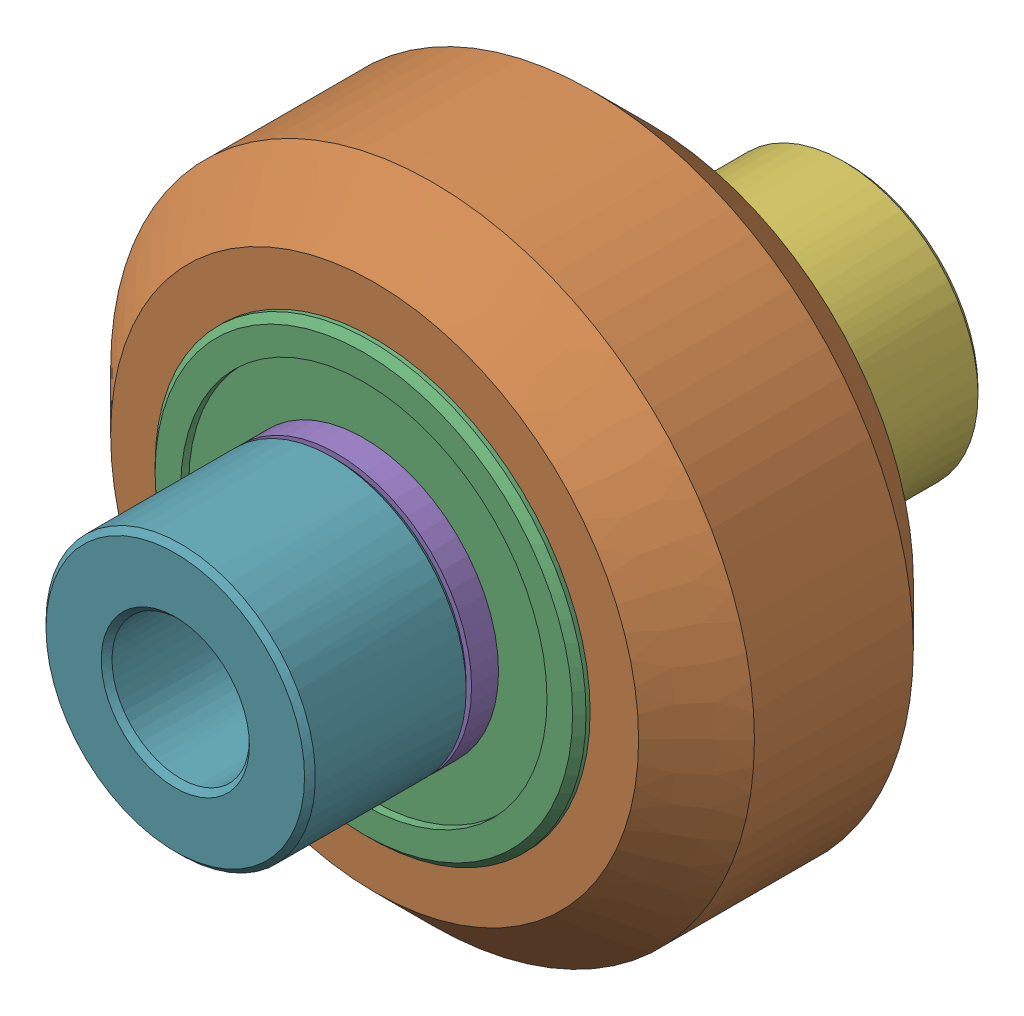
SolidWorks assembly Inboard Wheel Stack_3, configuration Default. Lengths in mm.
Overall size (23.9 23.9 25).
9 component instances, 4 part files, 0 mates.
Components (placement in the parent):
- Xtreme Solid V Wheel Kit Assembly_3-1: Xtreme Solid V Wheel Kit Assembly_3 [Default] at origin size (23.9 23.9 13)
  - Precision Shim - 10x5x1mm-1: Precision Shim - 10x5x1mm [Default] at origin size (10 10 1)
  - Xtreme Solid V Wheel Assembly_3-1: Xtreme Solid V Wheel Assembly_3 [Default] at (154.85 25 -23.5) size (23.9 23.9 11)
    - Xtreme Solid V Wheel-1: Xtreme Solid V Wheel [Default] at (-154.85 -25 30) x (0 0 1) z (-1 0 0) size (10.2 23.9 23.9)
    - Wheel+Kit+-+5x16x5mm+Sealed+Radial+Ball+Bearing.step.f3d-1: Wheel+Kit+-+5x16x5mm+Sealed+Radial+Ball+Bearing.step.f3d [Default] at (-154.85 -25 30) x (0 1 0) z (-1 0 0) size (16 5 16)
    - Wheel+Kit+-+5x16x5mm+Sealed+Radial+Ball+Bearing.step.f3d-2: Wheel+Kit+-+5x16x5mm+Sealed+Radial+Ball+Bearing.step.f3d [Default] at (-154.85 -25 30) x (0 1 0) z (1 0 0) size (16 5 16)
  - Precision Shim - 10x5x1mm-2: Precision Shim - 10x5x1mm [Default] at (0 0 12) size (10 10 1)
- Aluminum Spacer 6mm-1: Aluminum Spacer 6mm [Default] at (0 0 -6) size (10 10 6)
- Aluminum Spacer 6mm-2: Aluminum Spacer 6mm [Default] at (0 0 13) size (10 10 6)
